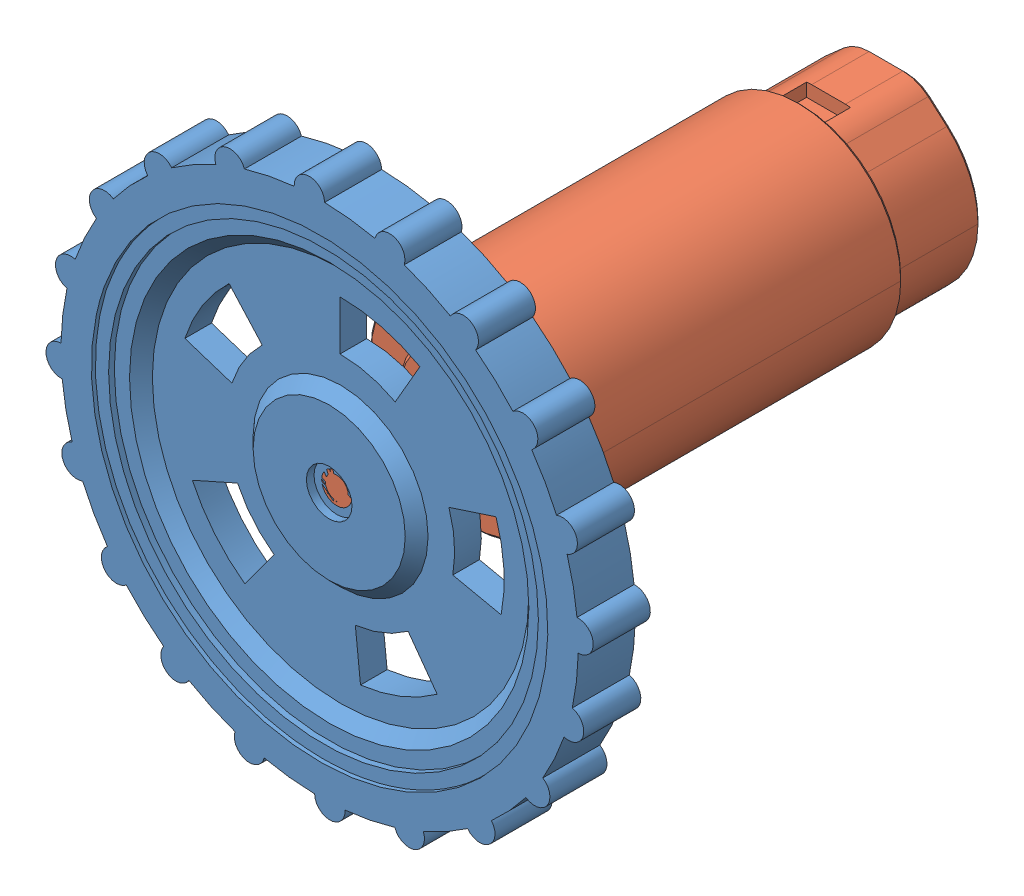
SolidWorks assembly Assem8, configuration Standard. Lengths in mm.
Overall size (70.15 70.15 73.03).
2 component instances, 2 part files, 2 mates.
Components (placement in the parent):
- Assembly1-1: Assembly1 [Standard] at (-17.1901 -9.934 70.1479) size (70.15 70.15 10.98)
- step_motor-10mm-2: step_motor-10mm [Standard] at (-12.5454 6.7237 -4.4904) size (26.3 26.3 70.83)
Mates (geometry in assembly coordinates):
- Concentric2: concentric aligned: cylinder of Assembly1-1 through (-12.5454 6.7237 77.0093) axis (0 0 -1) radius 1.4625; cylinder of step_motor-10mm-2 through (-12.5454 6.7237 77.0093) axis (0 0 -1) radius 2.1666
- Coincident5: coincident anti-aligned: circle of Assembly1-1; plane of step_motor-10mm-2 through (-12.5454 6.7237 77.0093) normal (0 0 1)
